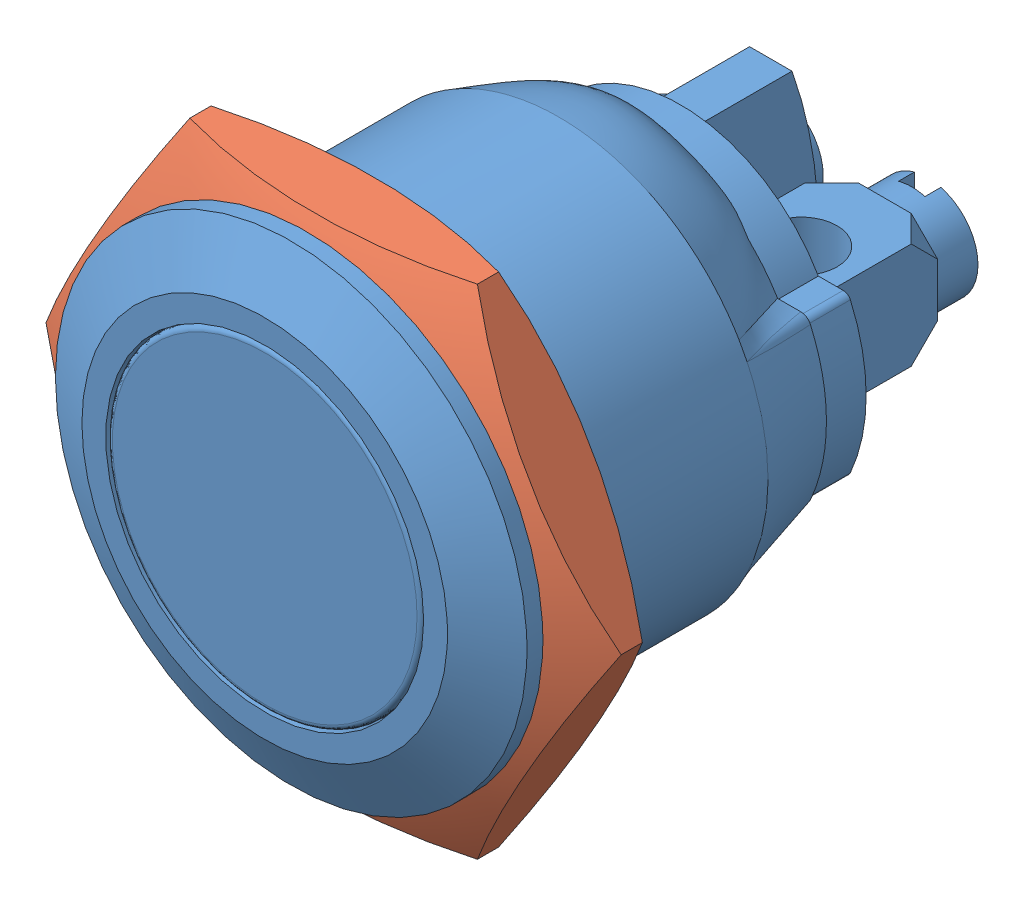
SolidWorks assembly button-without-ring, configuration Défaut. Lengths in mm.
Overall size (21.71 18.8 22.1).
2 component instances, 2 part files, 5 mates.
Components (placement in the parent):
- button-1: button [Défaut] at (-16.6108 4.4617 22.1) size (17.8 17.8 22.1)
- button-nut-1: button-nut [Défaut] at (-16.6108 4.4617 20.7) size (21.71 18.8 2.8)
Mates (geometry in assembly coordinates):
- Coaxiale1: concentric aligned: cylinder of button-1 through (-16.6108 4.4617 12.6) axis (0 0 1) radius 7.9; circle of button-ring-2
- Tangent3: tangent anti-aligned: plane of button-1 through (-16.6108 4.4617 22.1) normal (0 0 -1); torus of button-ring-2
- Coaxiale2: concentric: cylinder of button-1 through (-16.6108 4.4617 12.6) axis (0 0 1) radius 7.9; cylinder of button-nut-1 through (-16.6108 4.4617 20.3) axis (0 0 -1) radius 7.9
- Tangent4: tangent anti-aligned: plane of button-nut-1 through (-16.6108 4.4617 20.3) normal (0 0 1); torus of button-ring-2
- Coïncidente1: coincident anti-aligned: plane of button-1 through (-16.6108 4.4617 22.1) normal (0 0 -1); plane of button-nut-1 through (-16.6108 4.4617 22.1) normal (0 0 1)
